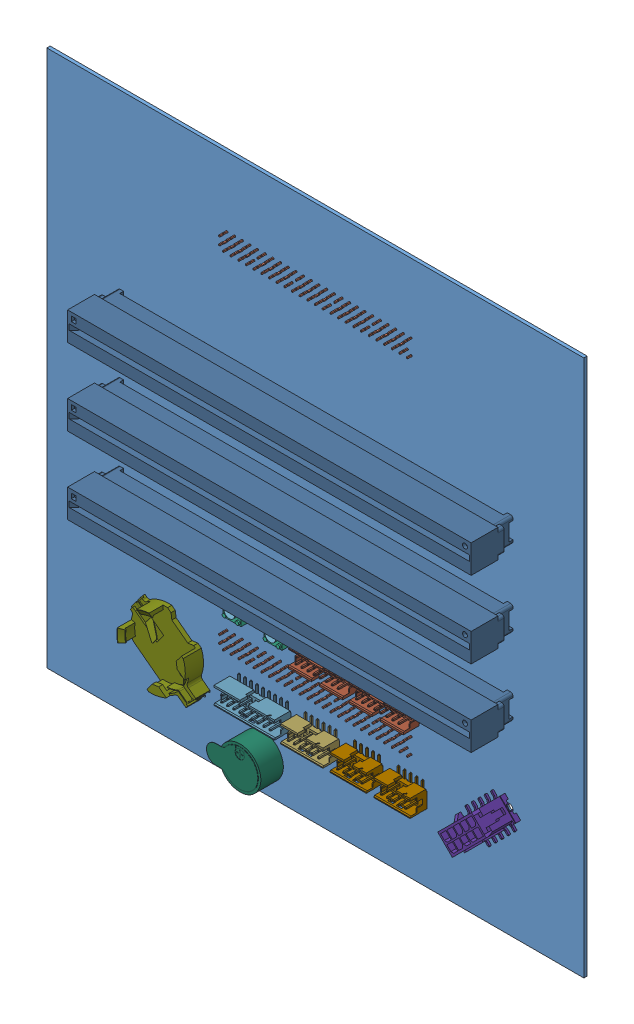
SolidWorks assembly Kanaloa_v2.0.0_Loko, configuration Default. Lengths in mm.
Overall size (177.8 177.8 24.47).
97 component instances, 17 part files, 0 mates.
Components (placement in the parent):
- Board_1-1: Board_1 [Default] at (0 0 -1.1024) size (177.8 177.8 1.1)
- Mez1Kanaloa_v2.0.0_Loko-1: Mez1Kanaloa_v2.0.0_Loko [Default] at origin size (67.06 7.24 10.54)
  - c-5536279-04-o1-3d-1: c-5536279-04-o1-3d [Default] at (114.9857 63.5255 -8.2144) x (-1 0 0) z (0 0 -1) size (67.06 7.24 10.54)
- R3_Motor_8Kanaloa_v2.0.0_Loko-1: R3_Motor_8Kanaloa_v2.0.0_Loko [Default] at origin size (1.3 2.38 0.85)
  - 330415056_1-1: 330415056_1 [Default] at (110.1463 80.2144 0) size (1.3 0.38 0.85)
    - Extruded_29-1: Extruded_29 [Default] at origin size (1.3 0.38 0.85)
  - 334787376_1-1: 334787376_1 [Default] at (110.1463 79.2144 0) size (1.27 2.2 0.85)
    - Extruded_30-1: Extruded_30 [Default] at origin size (1.27 2.2 0.85)
  - 330415056_1-2: 330415056_1 [Default] at (110.1463 78.2144 0) size (1.3 0.38 0.85)
    - Extruded_29-1: Extruded_29 [Default] at origin size (1.3 0.38 0.85)
- R3_Motor_7Kanaloa_v2.0.0_Loko-1: R3_Motor_7Kanaloa_v2.0.0_Loko [Default] at origin size (1.3 2.38 0.85)
  - 330415056_1-1: 330415056_1 [Default] at (97.0907 80.2144 0) size (1.3 0.38 0.85)
    - Extruded_29-1: Extruded_29 [Default] at origin size (1.3 0.38 0.85)
  - 334787376_1-1: 334787376_1 [Default] at (97.0907 79.2144 0) size (1.27 2.2 0.85)
    - Extruded_30-1: Extruded_30 [Default] at origin size (1.27 2.2 0.85)
  - 330415056_1-2: 330415056_1 [Default] at (97.0907 78.2144 0) size (1.3 0.38 0.85)
    - Extruded_29-1: Extruded_29 [Default] at origin size (1.3 0.38 0.85)
- Kanaloa_v2.0.0_Loko_1-1: Kanaloa_v2.0.0_Loko_1 [Default] at origin size (7.7 6 7.8)
  - OMRON-B3F_1000-1: OMRON-B3F_1000 [Default] at (90.1046 75.7682 0) x (1 0 0) z (0 -1 0) size (7.7 7.8 6)
    - OMRON-B3F_1000_B3F_1000_BUTTON-1: OMRON-B3F_1000_B3F_1000_BUTTON [Default] at (0 4.3 0) x (-1 0 0) z (0 0 -1) size (3.5 1 3.5)
    - OMRON-B3F_1000_B3F_1000_BASE-1: OMRON-B3F_1000_B3F_1000_BASE [Default] at origin size (7.7 7.4 6)
- Kanaloa_v2.0.0_Loko_2-1: Kanaloa_v2.0.0_Loko_2 [Default] at origin size (7.7 6 7.8)
  - OMRON-B3F_1000-1: OMRON-B3F_1000 [Default] at (103.6682 75.7682 0) x (1 0 0) z (0 -1 0) size (7.7 7.8 6)
    - OMRON-B3F_1000_B3F_1000_BUTTON-1: OMRON-B3F_1000_B3F_1000_BUTTON [Default] at (0 4.3 0) x (-1 0 0) z (0 0 -1) size (3.5 1 3.5)
    - OMRON-B3F_1000_B3F_1000_BASE-1: OMRON-B3F_1000_B3F_1000_BASE [Default] at origin size (7.7 7.4 6)
- R3_Motor_6Kanaloa_v2.0.0_Loko-1: R3_Motor_6Kanaloa_v2.0.0_Loko [Default] at origin size (1.3 2.38 0.85)
  - 330415056_1-1: 330415056_1 [Default] at (72.8083 75.9218 0) size (1.3 0.38 0.85)
    - Extruded_29-1: Extruded_29 [Default] at origin size (1.3 0.38 0.85)
  - 334787376_1-1: 334787376_1 [Default] at (72.8083 74.9218 0) size (1.27 2.2 0.85)
    - Extruded_30-1: Extruded_30 [Default] at origin size (1.27 2.2 0.85)
  - 330415056_1-2: 330415056_1 [Default] at (72.8083 73.9218 0) size (1.3 0.38 0.85)
    - Extruded_29-1: Extruded_29 [Default] at origin size (1.3 0.38 0.85)
- R3_Motor_5Kanaloa_v2.0.0_Loko-1: R3_Motor_5Kanaloa_v2.0.0_Loko [Default] at origin size (1.3 2.38 0.85)
  - 330415056_1-1: 330415056_1 [Default] at (64.2358 75.9554 0) size (1.3 0.38 0.85)
    - Extruded_29-1: Extruded_29 [Default] at origin size (1.3 0.38 0.85)
  - 334787376_1-1: 334787376_1 [Default] at (64.2358 74.9554 0) size (1.27 2.2 0.85)
    - Extruded_30-1: Extruded_30 [Default] at origin size (1.27 2.2 0.85)
  - 330415056_1-2: 330415056_1 [Default] at (64.2358 73.9554 0) size (1.3 0.38 0.85)
    - Extruded_29-1: Extruded_29 [Default] at origin size (1.3 0.38 0.85)
- R3_Motor_4Kanaloa_v2.0.0_Loko-1: R3_Motor_4Kanaloa_v2.0.0_Loko [Default] at origin size (1.3 2.38 0.85)
  - 330415056_1-1: 330415056_1 [Default] at (55.6633 75.9554 0) size (1.3 0.38 0.85)
    - Extruded_29-1: Extruded_29 [Default] at origin size (1.3 0.38 0.85)
  - 334787376_1-1: 334787376_1 [Default] at (55.6633 74.9554 0) size (1.27 2.2 0.85)
    - Extruded_30-1: Extruded_30 [Default] at origin size (1.27 2.2 0.85)
  - 330415056_1-2: 330415056_1 [Default] at (55.6633 73.9554 0) size (1.3 0.38 0.85)
    - Extruded_29-1: Extruded_29 [Default] at origin size (1.3 0.38 0.85)
- LED2_Motor_6Kanaloa_v2.0.0_Loko-1: LED2_Motor_6Kanaloa_v2.0.0_Loko [Default] at origin size (1.25 2 0.8)
  - 334788912-1: 334788912 [Default] at (72.7202 79.2355 0) size (1.15 1.38 0.8)
    - Extruded_31-1: Extruded_31 [Default] at origin size (1.15 1.38 0.8)
  - 425429200-1: 425429200 [Default] at (72.7202 79.248 0) size (1.25 2 0.3)
    - Extruded_32-1: Extruded_32 [Default] at origin size (1.25 2 0.3)
- LED2_Motor_5Kanaloa_v2.0.0_Loko-1: LED2_Motor_5Kanaloa_v2.0.0_Loko [Default] at origin size (1.25 2 0.8)
  - 334788912-1: 334788912 [Default] at (64.1477 79.2355 0) size (1.15 1.38 0.8)
    - Extruded_31-1: Extruded_31 [Default] at origin size (1.15 1.38 0.8)
  - 425429200-1: 425429200 [Default] at (64.1477 79.248 0) size (1.25 2 0.3)
    - Extruded_32-1: Extruded_32 [Default] at origin size (1.25 2 0.3)
- LED2_Motor_4Kanaloa_v2.0.0_Loko-1: LED2_Motor_4Kanaloa_v2.0.0_Loko [Default] at origin size (1.25 2 0.8)
  - 334788912-1: 334788912 [Default] at (55.5752 79.2355 0) size (1.15 1.38 0.8)
    - Extruded_31-1: Extruded_31 [Default] at origin size (1.15 1.38 0.8)
  - 425429200-1: 425429200 [Default] at (55.5752 79.248 0) size (1.25 2 0.3)
    - Extruded_32-1: Extruded_32 [Default] at origin size (1.25 2 0.3)
- Kanaloa_v2.0.0_Loko_3-1: Kanaloa_v2.0.0_Loko_3 [Default] at origin size (12 9 6.45)
  - s98424-x52-10LF-1: s98424-x52-10LF [Default] at (123.5965 51.5173 0.5842) size (12 9 6.45)
- Holo_NuiKanaloa_v2.0.0_Loko-1: Holo_NuiKanaloa_v2.0.0_Loko [Default] at origin size (133.6 9.35 18.67)
  - c-5645235-03-b-3d-1: c-5645235-03-b-3d [Default] at (114.3254 116.6876 15.24) size (133.6 9.35 18.67)
- Makeha_i_ka_LaniKanaloa_v2.0.0_Loko-1: Makeha_i_ka_LaniKanaloa_v2.0.0_Loko [Default] at origin size (133.6 9.35 18.67)
  - c-5645235-03-b-3d-1: c-5645235-03-b-3d [Default] at (114.3254 142.0876 15.24) size (133.6 9.35 18.67)
- Kanaloa_v2.0.0_Loko_4-1: Kanaloa_v2.0.0_Loko_4 [Default] at origin size (18 9 6.45)
  - s98424-x52-16LF-1: s98424-x52-16LF [Default] at (131.7929 74.7073 0.5842) x (-1 0 0) z (0 0 1) size (18 9 6.45)
- Mez2Kanaloa_v2.0.0_Loko-1: Mez2Kanaloa_v2.0.0_Loko [Default] at origin size (67.06 7.24 10.54)
  - c-5536279-04-o1-3d-1: c-5536279-04-o1-3d [Default] at (114.9857 177.8255 -8.2144) x (-1 0 0) z (0 0 -1) size (67.06 7.24 10.54)
- Kanaloa_v2.0.0_Loko_5-1: Kanaloa_v2.0.0_Loko_5 [Default] at origin size (12 9 6.45)
  - s98424-x52-10LF-1: s98424-x52-10LF [Default] at (138.0877 51.5173 0.5842) size (12 9 6.45)
- Kanaloa_v2.0.0_Loko_6-1: Kanaloa_v2.0.0_Loko_6 [Default] at origin size (14 9 6.45)
  - s98424-x52-12LF-1: s98424-x52-12LF [Default] at (107.2416 51.5171 0.5842) size (14 9 6.45)
- Kanaloa_v2.0.0_Loko_7-1: Kanaloa_v2.0.0_Loko_7 [Default] at origin size (18 9 6.45)
  - s98424-x52-16LF-1: s98424-x52-16LF [Default] at (151.8655 74.7073 0.5842) x (-1 0 0) z (0 0 1) size (18 9 6.45)
- Holoholo_KaiKanaloa_v2.0.0_Loko-1: Holoholo_KaiKanaloa_v2.0.0_Loko [Default] at origin size (133.6 9.35 18.67)
  - c-5645235-03-b-3d-1: c-5645235-03-b-3d [Default] at (114.3254 91.2876 15.24) size (133.6 9.35 18.67)
- Kanaloa_v2.0.0_Loko_8-1: Kanaloa_v2.0.0_Loko_8 [Default] at origin size (2.5 3.5 1)
  - 378153280_1-1: 378153280_1 [Default] at (58.932 74.8538 0) size (2.5 3.5 1)
    - Extruded_33-1: Extruded_33 [Default] at origin size (2.5 3.5 1)
- Kanaloa_v2.0.0_Loko_9-1: Kanaloa_v2.0.0_Loko_9 [Default] at origin size (2.5 3.5 1)
  - 378153280_1-1: 378153280_1 [Default] at (67.568 74.8538 0) size (2.5 3.5 1)
    - Extruded_33-1: Extruded_33 [Default] at origin size (2.5 3.5 1)
- Kanaloa_v2.0.0_Loko_10-1: Kanaloa_v2.0.0_Loko_10 [Default] at origin size (2.5 3.5 1)
  - 378153280_1-1: 378153280_1 [Default] at (76.1024 74.8538 0) size (2.5 3.5 1)
    - Extruded_33-1: Extruded_33 [Default] at origin size (2.5 3.5 1)
- Kanaloa_v2.0.0_Loko_11-1: Kanaloa_v2.0.0_Loko_11 [Default] at origin size (20 9 6.45)
  - s98424-x52-18LF-1: s98424-x52-18LF [Default] at (85.1945 51.5173 0.5842) size (20 9 6.45)
- Kanaloa_v2.0.0_Loko_12-1: Kanaloa_v2.0.0_Loko_12 [Default] at origin size (17.9 13.8 13.05)
  - pui_speaker_AI-1433-TWT-R-1: pui_speaker_AI-1433-TWT-R [Default] at (96.9264 36.2712 7.62) x (0 1 0) z (0 0 -1) size (13.8 17.9 13.05)
- Kanaloa_v2.0.0_Loko_13-1: Kanaloa_v2.0.0_Loko_13 [Default] at origin size (33.27 31.65 9.45)
  - te_battery_clip_120591-1-j1-3d-1: te_battery_clip_120591-1-j1-3d [Default] at (66.5698 53.403 2.032) x (-0.798636 0.601815 0) z (0 0 1) size (27.31 19.05 9.45)
- Kanaloa_v2.0.0_Loko_14-1: Kanaloa_v2.0.0_Loko_14 [Default] at origin size (21.46 21.46 11.91)
  - 430451016-1: 430451016 [Default] at (172.7454 56.1341 4.953) x (0.707107 0.707107 0) z (0 0 1) size (19.15 11.2 11.91)
    - Open CASCADE STEP translator 6.2 1.28.1.1-1: Open CASCADE STEP translator 6.2 1.28.1.1 [Default] at origin size (19.15 11.2 11.91)
